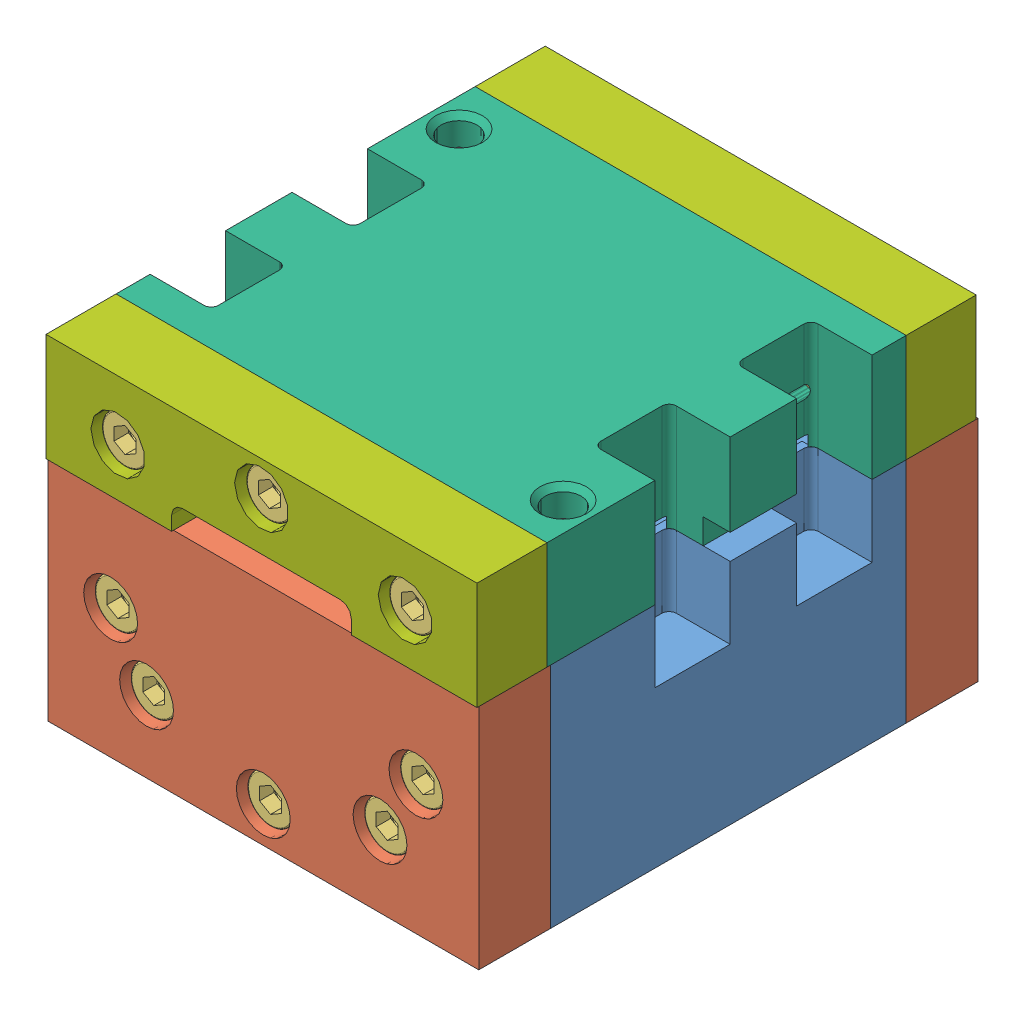
SolidWorks assembly ЧМВ1.02.00 - Сборка всех деталей, configuration Default. Lengths in mm.
Overall size (120 93.5 139.5).
30 component instances, 7 part files, 3 mates.
Components (placement in the parent):
-  ЧМВ1.01.00 - Сборка Матрицы-1:  ЧМВ1.01.00 - Сборка Матрицы [По умолчанию] at (46.1455 48.573 101.7886) size (120 88.5 139)
  - ЧМВ1.01.02 - Матрица-1: ЧМВ1.01.02 - Матрица [Default] at origin size (120 63.5 99)
  - ЧМВ1.01.02 - Боковина Пресс-формы-1: ЧМВ1.01.02 - Боковина Пресс-формы [По умолчанию] at (0 36.1757 49.5) size (120 63.5 20)
  - ЧМВ1.01.02 - Боковина Пресс-формы-3: ЧМВ1.01.02 - Боковина Пресс-формы [По умолчанию] at (0 36.1757 -49.5) x (-1 0 0) z (0 0 -1) size (120 63.5 20)
  - socket head cap screw_iso-1: socket head cap screw_iso [ISO 4762 M8 x 16 - 16N] at (-42.5 36 -67.5) x (0 0 1) z (-1 0 0) size (24 13 13)
  - socket head cap screw_iso-2: socket head cap screw_iso [ISO 4762 M8 x 16 - 16N] at (-32.5 20 -67.5) x (0 0 1) z (-1 0 0) size (24 13 13)
  - socket head cap screw_iso-3: socket head cap screw_iso [ISO 4762 M8 x 16 - 16N] at (0 10 -67.5) x (0 0 1) z (-1 0 0) size (24 13 13)
  - socket head cap screw_iso-4: socket head cap screw_iso [ISO 4762 M8 x 16 - 16N] at (32.5 20 -67.5) x (0 0 1) z (-1 0 0) size (24 13 13)
  - socket head cap screw_iso-5: socket head cap screw_iso [ISO 4762 M8 x 16 - 16N] at (42.5 36 -67.5) x (0 0 1) z (-1 0 0) size (24 13 13)
  - socket head cap screw_iso-6: socket head cap screw_iso [ISO 4762 M8 x 16 - 16N] at (42.5 36 67.5) x (0 0 -1) z (1 0 0) size (24 13 13)
  - socket head cap screw_iso-7: socket head cap screw_iso [ISO 4762 M8 x 16 - 16N] at (32.5 20 67.5) x (0 0 -1) z (1 0 0) size (24 13 13)
  - socket head cap screw_iso-10: socket head cap screw_iso [ISO 4762 M8 x 16 - 16N] at (-42.5 36 67.5) x (0 0 -1) z (1 0 0) size (24 13 13)
  - socket head cap screw_iso-8: socket head cap screw_iso [ISO 4762 M8 x 16 - 16N] at (0 10 67.5) x (0 0 -1) z (1 0 0) size (24 13 13)
  - socket head cap screw_iso-9: socket head cap screw_iso [ISO 4762 M8 x 16 - 16N] at (-32.5 20 67.5) x (0 0 -1) z (1 0 0) size (24 13 13)
  - socket head cap screw_iso-11: socket head cap screw_iso [ISO 4762 M8 x 16 - 16N] at (-32.5 20 67.5) x (0 0 -1) z (1 0 0) size (24 13 13)
  - socket head cap screw_iso-12: socket head cap screw_iso [ISO 4762 M8 x 16 - 16N] at (-42.5 36 67.5) x (0 0 -1) z (1 0 0) size (24 13 13)
  - ЧМВ1.01.03 - Направляющая-1: ЧМВ1.01.03 - Направляющая [Default] at (52 33.5 38) x (0 1 0) z (-0.458497 0 -0.888696) size (55 10 10)
  - ЧМВ1.01.03 - Направляющая-3: ЧМВ1.01.03 - Направляющая [Default] at (-51.997 33.5 -37) x (0 1 0) z (-0.61776 0 -0.786366) size (55 10 10)
  - ЧМВ1.01.04 - Подставка-2: ЧМВ1.01.04 - Подставка [По умолчанию] at (0 48 -27) x (0.955678 0 -0.294415) z (0 -1 0) size (12 12 36)
  - ЧМВ1.01.04 - Подставка-3: ЧМВ1.01.04 - Подставка [По умолчанию] at (0 48 27) x (0.972927 0 -0.231111) z (0 -1 0) size (12 12 36)
- ЧМВ1.03.00 - Сборка пуансона -1: ЧМВ1.03.00 - Сборка пуансона  [По умолчанию] at (-38.641 -37.4362 -141.29) size (120 30 139)
  - ЧМВ1.03.02 -Пуансон-2: ЧМВ1.03.02 -Пуансон [Default] at (84.7865 149.5092 243.5787) size (120 30 100)
  - ЧМВ1.03.01 - Боковина пуансона-3: ЧМВ1.03.01 - Боковина пуансона [Default] at (84.7865 164.5092 193.5787) x (1 0 0) z (0 0 -1) size (120 30 19.5)
  - ЧМВ1.03.01 - Боковина пуансона-4: ЧМВ1.03.01 - Боковина пуансона [Default] at (84.7865 164.5092 293.5787) x (-1 0 0) z (0 0 1) size (120 30 19.5)
  - socket head cap screw_iso-1: socket head cap screw_iso [ISO 4762 M8 x 16 - 16N] at (44.7865 163.0092 311.0787) x (0 0 -1) z (1 0 0) size (24 13 13)
  - socket head cap screw_iso-2: socket head cap screw_iso [ISO 4762 M8 x 16 - 16N] at (124.7865 163.0092 311.0787) x (0 0 -1) z (1 0 0) size (24 13 13)
  - socket head cap screw_iso-3: socket head cap screw_iso [ISO 4762 M8 x 16 - 16N] at (85.1489 170.29 311.2498) x (0 0 -1) z (1 0 0) size (24 13 13)
  - socket head cap screw_iso-4: socket head cap screw_iso [ISO 4762 M8 x 16 - 16N] at (124.7865 163.0092 176.0787) x (0 0 1) z (-1 0 0) size (24 13 13)
  - socket head cap screw_iso-5: socket head cap screw_iso [ISO 4762 M8 x 16 - 16N] at (84.7865 170.0092 176.0787) x (0 0 1) z (-1 0 0) size (24 13 13)
  - socket head cap screw_iso-6: socket head cap screw_iso [ISO 4762 M8 x 16 - 16N] at (44.7865 163.0092 176.0787) x (0 0 1) z (-1 0 0) size (24 13 13)
Mates (geometry in assembly coordinates):
- Концентричный25: concentric aligned: cylinder of Сборка3-1/Пуансон-2 through (-5.8515 164.073 64.7886) axis (0 -1 0) radius 5; cylinder of Сборка1-1/Направляющая-3 through (-5.8515 82.073 64.7886) axis (0 -1 0) radius 5
- Концентричный29: concentric anti-aligned: cylinder of  ЧМВ1.01.00 - Сборка Матрицы-1/ЧМВ1.01.02 - Матрица-1 through (98.1455 82.073 139.7886) axis (0 1 0) radius 5; cylinder of Сборка3-1/Пуансон-2 through (98.1455 164.073 139.7886) axis (0 -1 0) radius 5
- Совпадение3: coincident anti-aligned: plane of Сборка1-1/Боковина Пресс-формы.-1 through (-13.8545 112.073 171.2886) normal (0 1 0); plane of Сборка3-1/Боковина пуансона-4 through (-13.8545 112.073 171.7886) normal (0 -1 0)
